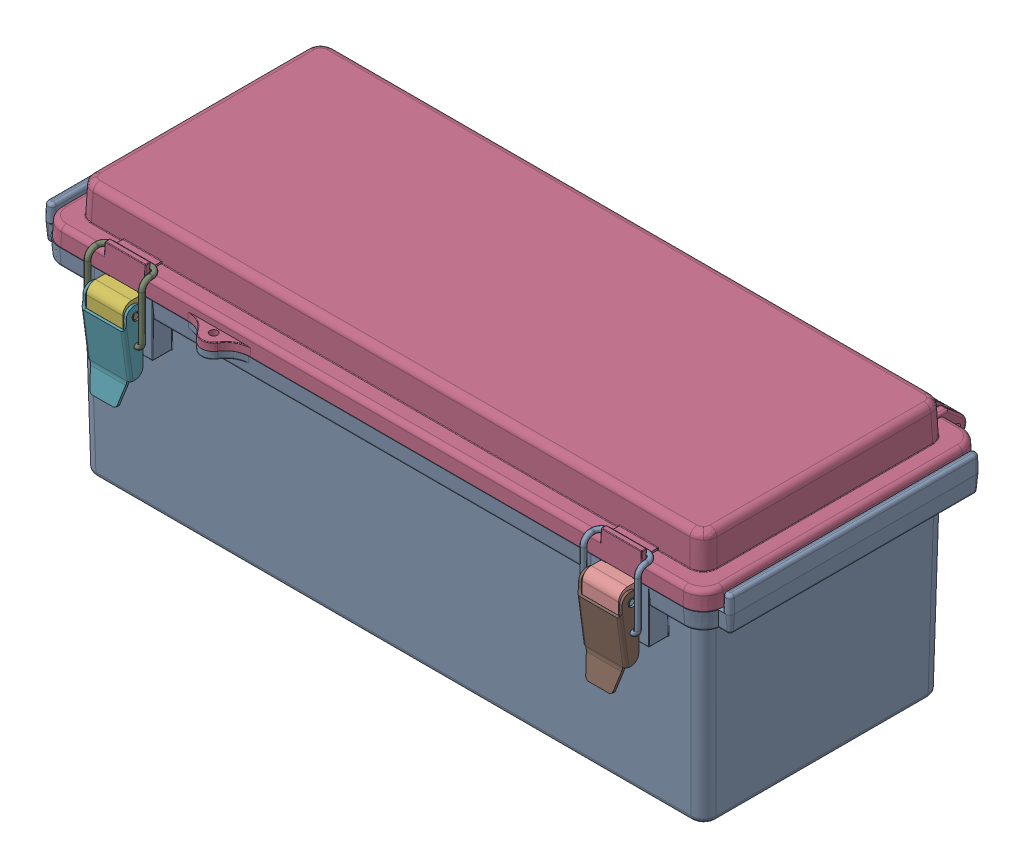
SolidWorks assembly WQ-42S_WQ-42S-03, configuration Default. Lengths in mm.
Overall size (268.67 101.69 126.73).
14 component instances, 7 part files, 0 mates.
Components (placement in the parent):
- WQ-42B_WQ-42B-02-1: WQ-42B_WQ-42B-02 [Default] at origin size (268.67 88.37 124.85)
- WQ-42C_WQ-42C-03-1: WQ-42C_WQ-42C-03 [Default] x (-1 0 0) z (0 0 1) size (259.4 24.02 124.85)
- WQ-50L-01_DEFAULT-1: WQ-50L-01_DEFAULT [Default] at (-97 -21 48.2) size (23.23 44.9 15.28)
  - BASE^WQ-50L-01-1: BASE^WQ-50L-01 [Default] at origin size (16 21 14.2)
  - FRONT^WQ-50L-01_default-1: FRONT^WQ-50L-01_default [Default] at (0 12.75 15.1) size (17.35 34.89 7.58)
  - PIN^WQ-50L-01-1: PIN^WQ-50L-01 [Default] at (0 16.5 10.7) size (18.22 3.75 3.75)
  - LOOP^WQ-50L-01-1: LOOP^WQ-50L-01 [Default] at (0 6 10.2) x (1 0 0) z (0 0 -1) size (23.23 25.83 8.77)
- WQ-50L-01_DEFAULT-2: WQ-50L-01_DEFAULT [Default] at (97 -21 48.2) size (23.23 44.9 15.28)
  - BASE^WQ-50L-01-1: BASE^WQ-50L-01 [Default] at origin size (16 21 14.2)
  - FRONT^WQ-50L-01_default-1: FRONT^WQ-50L-01_default [Default] at (0 12.75 15.1) size (17.35 34.89 7.58)
  - PIN^WQ-50L-01-1: PIN^WQ-50L-01 [Default] at (0 16.5 10.7) size (18.22 3.75 3.75)
  - LOOP^WQ-50L-01-1: LOOP^WQ-50L-01 [Default] at (0 6 10.2) x (1 0 0) z (0 0 -1) size (23.23 25.83 8.77)
- WQ-PIN-01-1: WQ-PIN-01 [Default] at (-97.8004 0 -59.1739) x (1 0 0) z (0 0.80624 0.591589) size (34.89 4.76 4.76)
- WQ-PIN-01-2: WQ-PIN-01 [Default] at (96.1996 0 -59.1739) x (1 0 0) z (0 0.80624 0.591589) size (34.89 4.76 4.76)
